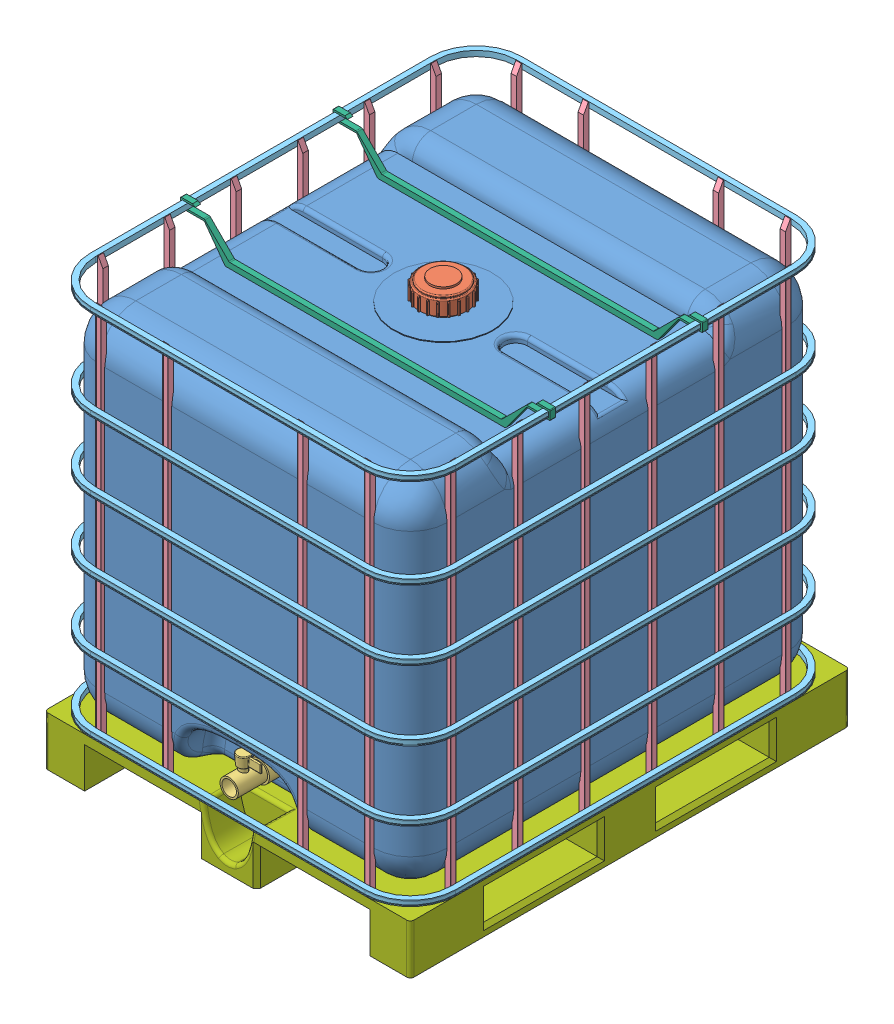
SolidWorks assembly zbiornik_1000L, configuration Domyślna. Lengths in mm.
Overall size (1010 1160 1200.03).
35 component instances, 7 part files, 0 mates.
Components (placement in the parent):
- zbiornik_1000L.stp-1: zbiornik_1000L.stp [Domyślna] at origin size (1010 1160 1200.03)
  - Tank in cage.stp-1: Tank in cage.stp [Domyślna] at (13.1673 69.1203 -90.9296) size (1010 1049.55 1180)
    - TankAssy.stp-1: TankAssy.stp [Domyślna] at (-6.2963 19.0708 -12.9952) size (950.1 1007.98 1150)
      - IBC tank body.stp-1: IBC tank body.stp [Domyślna] at (1.4815 -1.0627 -565.0048) size (950.1 994.6 1130.05)
      - tank lid.stp-1: tank lid.stp [Domyślna] at (1.4815 437.3652 -0.0048) size (138.09 60 138.09)
      - Tank nozzle.stp-1: Tank nozzle.stp [Domyślna] at (1.4815 -421.0627 464.9952) size (80 95 120)
    - cagevertical.stp-1: cagevertical.stp [Domyślna] at (472.6852 -466.992 444.5) x (0 0 1) z (-1 0 0) size (15 1020 15)
    - cagevertical.stp-2: cagevertical.stp [Domyślna] at (472.6852 -466.992 261.5) x (0 0 1) z (-1 0 0) size (15 1020 15)
    - cagevertical.stp-3: cagevertical.stp [Domyślna] at (472.6852 -466.992 78.5) x (0 0 1) z (-1 0 0) size (15 1020 15)
    - cagevertical.stp-4: cagevertical.stp [Domyślna] at (472.6852 -466.992 -104.5) x (0 0 1) z (-1 0 0) size (15 1020 15)
    - cagevertical.stp-5: cagevertical.stp [Domyślna] at (472.6852 -466.992 -287.5) x (0 0 1) z (-1 0 0) size (15 1020 15)
    - cagevertical.stp-6: cagevertical.stp [Domyślna] at (472.6852 -466.992 -470.5) x (0 0 1) z (-1 0 0) size (15 1020 15)
    - cagevertical.stp-7: cagevertical.stp [Domyślna] at (362.6852 -466.992 554.5) x (-1 0 0) z (0 0 -1) size (15 1020 15)
    - cagevertical.stp-8: cagevertical.stp [Domyślna] at (179.6852 -466.992 554.5) x (-1 0 0) z (0 0 -1) size (15 1020 15)
    - cagevertical.stp-9: cagevertical.stp [Domyślna] at (-189.3148 -466.992 554.5) x (-1 0 0) z (0 0 -1) size (15 1020 15)
    - cagevertical.stp-10: cagevertical.stp [Domyślna] at (-372.3148 -466.992 554.5) x (-1 0 0) z (0 0 -1) size (15 1020 15)
    - cagevertical.stp-11: cagevertical.stp [Domyślna] at (-482.3148 -466.992 -470.5) x (0 0 -1) z (1 0 0) size (15 1020 15)
    - cagevertical.stp-12: cagevertical.stp [Domyślna] at (-482.3148 -466.992 -288.5) x (0 0 -1) z (1 0 0) size (15 1020 15)
    - cagevertical.stp-13: cagevertical.stp [Domyślna] at (-482.3148 -466.992 -106.5) x (0 0 -1) z (1 0 0) size (15 1020 15)
    - cagevertical.stp-14: cagevertical.stp [Domyślna] at (-482.3148 -466.992 75.5) x (0 0 -1) z (1 0 0) size (15 1020 15)
    - cagevertical.stp-15: cagevertical.stp [Domyślna] at (-482.3148 -466.992 257.5) x (0 0 -1) z (1 0 0) size (15 1020 15)
    - cagevertical.stp-16: cagevertical.stp [Domyślna] at (-482.3148 -466.992 439.5) x (0 0 -1) z (1 0 0) size (15 1020 15)
    - cagevertical.stp-17: cagevertical.stp [Domyślna] at (362.6852 -466.992 -580.5) size (15 1020 15)
    - cagevertical.stp-18: cagevertical.stp [Domyślna] at (-189.3148 -466.992 -580.5) size (15 1020 15)
    - cagevertical.stp-19: cagevertical.stp [Domyślna] at (179.6852 -466.992 -580.5) size (15 1020 15)
    - cagevertical.stp-20: cagevertical.stp [Domyślna] at (-372.3148 -466.992 -580.5) size (15 1020 15)
    - cagehoop.stp-1: cagehoop.stp [Domyślna] at (-4.8148 545.508 -13) x (0 0 -1) z (1 0 0) size (1180 15 1000)
    - cagehoop.stp-2: cagehoop.stp [Domyślna] at (-4.8148 -459.492 -13) x (0 0 -1) z (1 0 0) size (1180 15 1000)
    - cagehoop.stp-3: cagehoop.stp [Domyślna] at (-4.8148 -269.492 -13) x (0 0 -1) z (1 0 0) size (1180 15 1000)
    - cagehoop.stp-4: cagehoop.stp [Domyślna] at (-4.8148 -79.492 -13) x (0 0 -1) z (1 0 0) size (1180 15 1000)
    - cagehoop.stp-5: cagehoop.stp [Domyślna] at (-4.8148 110.508 -13) x (0 0 -1) z (1 0 0) size (1180 15 1000)
    - cagehoop.stp-6: cagehoop.stp [Domyślna] at (-4.8148 300.508 -13) x (0 0 -1) z (1 0 0) size (1180 15 1000)
    - Cage Top.stp-1: Cage Top.stp [Domyślna] at (-4.8148 496.508 185) size (1010 103 15)
    - Cage Top.stp-2: Cage Top.stp [Domyślna] at (-4.8148 496.508 -231) size (1010 103 15)
  - PALLET.stp-1: PALLET.stp [Domyślna] at (8.3525 -465.3717 -713.9296) size (1000 136.82 1200.03)
